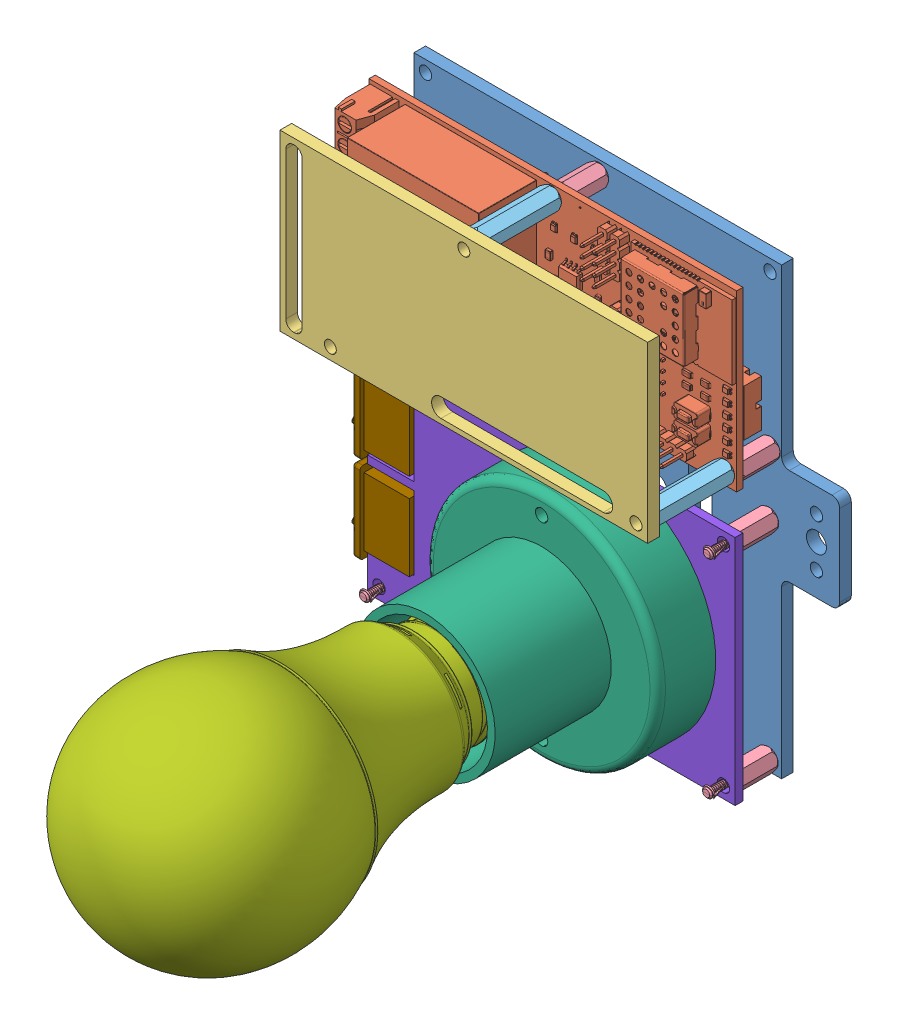
SolidWorks assembly Assem, configuration Default. Lengths in mm.
Overall size (137.27 153.42 149.57).
18 component instances, 9 part files, 43 mates.
Components (placement in the parent):
- frame_rtls-1: frame_rtls [Default] at (-50.2519 61.609 0) size (125.02 115.01 3)
- RTLS-1: RTLS [Default] at (0 118.9041 14.6194) x (-1 0 0) z (0 0 1) size (100.23 52.22 33.77)
- frame_rtls_top-1: frame_rtls_top [Default] at (-39.2593 131.0198 34.6194) x (-1 0 0) z (0 0 1) size (95 45.01 3)
- Hex Spacer MF M3 L10mm.stp-1: Hex Spacer MF M3 L10mm.stp [Default] at (-120.6382 86.5408 13) x (0.972076 -0.234665 0) z (0 0 1) size (35.27 35.27 35.27)
- Hex Spacer MF M3 L10mm.stp-2: Hex Spacer MF M3 L10mm.stp [Default] at (-87.1957 116.7477 13) x (0.999688 -0.024974 0) z (0 0 1) size (35.27 35.27 35.27)
- Hex Spacer MF M3 L10mm.stp-3: Hex Spacer MF M3 L10mm.stp [Default] at (-39.7266 61.0145 13) x (0.921221 0.38904 0) z (0 0 1) size (35.27 35.27 35.27)
- Hex Spacer MF M3 L20mm.stp-1: Hex Spacer MF M3 L20mm.stp [Default] at (136.3996 89.8518 14.6194) x (-0.995937 -0.090058 0) z (0 0 -1) size (35.27 35.27 37.7)
- Hex Spacer MF M3 L20mm.stp-2: Hex Spacer MF M3 L20mm.stp [Default] at (-122.1152 -2.5556 14.6194) x (0.530847 0.847468 0) z (0 0 -1) size (35.27 35.27 37.7)
- Hex Spacer MF M3 L20mm.stp-3: Hex Spacer MF M3 L20mm.stp [Default] at (-150.1721 -44.9927 14.6194) x (0.488573 0.872523 0) z (0 0 -1) size (35.27 35.27 37.7)
- lightBulbHolder-1: lightBulbHolder [Default] at (-35.021 33.8951 30) x (0 -1 0) z (0 0 -1) size (60 60 45)
- E27 400L-1: E27 400L [Default] at (-62.6296 46.4675 35) x (0.913942 -0.405844 0) z (-0.405844 -0.913942 0) size (61.78 110 61.78)
- frame_rtls_mid-1: frame_rtls_mid [Default] at (-55.4574 45.0136 13) size (95 60 2)
- Hex Spacer MF M3 L10mm.stp-4: Hex Spacer MF M3 L10mm.stp [Default] at (-5.8964 20.6716 13) x (0.066123 0.997811 0) z (0 0 1) size (35.27 35.27 35.27)
- Hex Spacer MF M3 L10mm.stp-5: Hex Spacer MF M3 L10mm.stp [Default] at (-116.6357 28.8809 13) x (0.607256 0.794506 0) z (0 0 1) size (35.27 35.27 35.27)
- Hex Spacer MF M3 L10mm.stp-6: Hex Spacer MF M3 L10mm.stp [Default] at (-96.1069 -33.2978 13) x (0.101079 0.994878 0) z (0 0 1) size (35.27 35.27 35.27)
- Hex Spacer MF M3 L10mm.stp-7: Hex Spacer MF M3 L10mm.stp [Default] at (-5.1443 -33.0494 13) x (0.043617 0.999048 0) z (0 0 1) size (35.27 35.27 35.27)
- rocker_switch-1: rocker_switch [test] at (-97.021 45.1451 9.45) x (0 0 1) z (-1 0 0) size (15 21 21.16)
- rocker_switch-2: rocker_switch [test] at (-97.021 22.6451 9.45) x (0 0 1) z (-1 0 0) size (15 21 21.16)
Mates (geometry in assembly coordinates):
- Coincident59: coincident aligned: plane of RTLS-1 through (0 118.9041 13) normal (1 0 0); plane of frame_rtls-1 through (0 46.8951 3) normal (1 0 0)
- Coincident60: coincident anti-aligned: plane of frame_rtls-1 through (2 75.9041 0) normal (0 0 -1)
- Coincident61: coincident anti-aligned: plane of frame_rtls-1 through (2 75.9041 3) normal (0 0 1); plane of Hex Spacer MF M3 L10mm.stp-1 through (-84.8324 75.2738 3) normal (0 0 -1)
- Tangent1: tangent anti-aligned: cylinder of frame_rtls-1 through (-82 76.9041 3) axis (0 0 -1) radius 1.55; face of Hex Spacer MF M3 L10mm.stp-1
- Coincident63: coincident anti-aligned: plane of frame_rtls-1 through (2 75.9041 3) normal (0 0 1); plane of Hex Spacer MF M3 L10mm.stp-3 through (-4.2348 73.235 3) normal (0 0 -1)
- Coincident64: coincident aligned: plane of frame_rtls-1 through (0 46.8951 3) normal (1 0 0)
- Tangent2: tangent anti-aligned: cylinder of frame_rtls-1 through (-3 76.9041 3) axis (0 0 -1) radius 1.55; edge_curve of Hex Spacer MF M3 L10mm.stp-3
- Coincident65: coincident anti-aligned: plane of frame_rtls-1 through (2 75.9041 3) normal (0 0 1); plane of Hex Spacer MF M3 L10mm.stp-2 through (-49.821 113.2632 3) normal (0 0 -1)
- Tangent3: tangent anti-aligned: cylinder of frame_rtls-1 through (-47.5105 115.925 3) axis (0 0 -1) radius 1.55; edge_curve of Hex Spacer MF M3 L10mm.stp-2
- Coincident66: coincident anti-aligned: plane of RTLS-1 through (0 118.9041 13) normal (0 0 -1); plane of Hex Spacer MF M3 L10mm.stp-3 through (-4.2348 73.235 13) normal (0 0 1)
- Coincident67: coincident anti-aligned: plane of frame_rtls-1 through (2 75.9041 3) normal (0 0 1); plane of Hex Spacer MF M3 L10mm.stp-5 through (-91.868 57.0867 3) normal (0 0 -1)
- Coincident68: coincident anti-aligned: plane of frame_rtls-1 through (2 75.9041 3) normal (0 0 1); plane of Hex Spacer MF M3 L10mm.stp-4 through (-0.8757 57.871 3) normal (0 0 -1)
- Coincident69: coincident anti-aligned: plane of frame_rtls-1 through (2 75.9041 3) normal (0 0 1); plane of Hex Spacer MF M3 L10mm.stp-6 through (-89.7846 3.7027 3) normal (0 0 -1)
- Coincident70: coincident anti-aligned: plane of frame_rtls-1 through (2 75.9041 3) normal (0 0 1); plane of Hex Spacer MF M3 L10mm.stp-7 through (-0.9633 4.2537 3) normal (0 0 -1)
- Tangent4: tangent anti-aligned: cylinder of frame_rtls-1 through (-3 6.8951 3) axis (0 0 -1) radius 1.6; edge_curve of Hex Spacer MF M3 L10mm.stp-7
- Tangent5: tangent anti-aligned: cylinder of frame_rtls-1 through (-3 60.8951 3) axis (0 0 -1) radius 1.6; edge_curve of Hex Spacer MF M3 L10mm.stp-4
- Tangent6: tangent anti-aligned: cylinder of frame_rtls-1 through (-92.021 6.8951 3) axis (0 0 -1) radius 1.6; edge_curve of Hex Spacer MF M3 L10mm.stp-6
- Tangent7: tangent anti-aligned: cylinder of frame_rtls-1 through (-92.021 60.8951 3) axis (0 0 -1) radius 1.6; edge_curve of Hex Spacer MF M3 L10mm.stp-5
- Coincident71: coincident anti-aligned: plane of lightBulbHolder-1 through (-35.021 33.8951 35) normal (0 0 1); plane of E27 400L-1 through (-35.2113 34.2922 35) normal (0 0 -1)
- Tangent8: tangent aligned: cylinder of lightBulbHolder-1 through (-35.021 33.8951 60) axis (0 0 -1) radius 18; edge_curve of E27 400L-1
- Coincident80: coincident anti-aligned: plane of RTLS-1 through (0 118.9041 14.6194) normal (0 0 1); plane of Hex Spacer MF M3 L20mm.stp-3 through (-85.2428 76.1815 14.6194) normal (0 0 -1)
- Coincident81: coincident anti-aligned: plane of RTLS-1 through (0 118.9041 14.6194) normal (0 0 1); plane of Hex Spacer MF M3 L20mm.stp-1 through (-0.2622 74.9336 14.6194) normal (0 0 -1)
- Coincident82: coincident anti-aligned: plane of RTLS-1 through (0 118.9041 14.6194) normal (0 0 1); plane of Hex Spacer MF M3 L20mm.stp-2 through (-51.3113 115.2825 14.6194) normal (0 0 -1)
- Coincident86: coincident aligned: plane of frame_rtls-1 through (0 46.8951 3) normal (1 0 0); plane of frame_rtls_top-1 through (0 73.8951 37.6194) normal (1 0 0)
- Coincident87: coincident anti-aligned: plane of frame_rtls_top-1 through (-39.2593 131.0198 34.6194) normal (0 0 -1); plane of Hex Spacer MF M3 L20mm.stp-1 through (-0.2622 74.9336 34.6194) normal (0 0 1)
- Tangent14: tangent anti-aligned: cylinder of frame_rtls_top-1 through (-3 76.8951 37.6194) axis (0 0 -1) radius 1.55; edge_curve of Hex Spacer MF M3 L20mm.stp-1
- Tangent15: tangent anti-aligned: cylinder of frame_rtls_top-1 through (-82 76.8951 37.6194) axis (0 0 -1) radius 1.55; edge_curve of Hex Spacer MF M3 L20mm.stp-3
- Tangent16: tangent anti-aligned: cylinder of frame_rtls_top-1 through (-47.5 115.9041 37.6194) axis (0 0 -1) radius 1.55; edge_curve of Hex Spacer MF M3 L20mm.stp-2
- Coincident88: coincident anti-aligned: plane of frame_rtls-1 through (2 75.9041 3) normal (0 0 1); plane of rocker_switch-1 through (-83.321 36.3951 3) normal (0 0 -1)
- Coincident89: coincident anti-aligned: plane of frame_rtls-1 through (2 75.9041 3) normal (0 0 1); plane of rocker_switch-2 through (-83.321 13.8951 3) normal (0 0 -1)
- Coincident94: coincident anti-aligned: plane of frame_rtls-1 through (2 75.9041 3) normal (0 0 1); plane of rocker_switch-1 through (-83.321 36.3951 3) normal (0 0 -1)
- Coincident95: coincident anti-aligned: plane of frame_rtls_mid-1 through (-95.021 53.8951 15) normal (0 -1 0); plane of rocker_switch-1 through (-83.321 53.8951 15.9) normal (0 1 0)
- Coincident96: coincident anti-aligned: plane of frame_rtls_mid-1 through (-95.021 63.8951 15) normal (-1 0 0); plane of rocker_switch-1 through (-95.021 55.6451 1.95) normal (1 0 0)
- Coincident98: coincident anti-aligned: plane of frame_rtls_mid-1 through (-55.4574 45.0136 13) normal (0 0 -1); plane of Hex Spacer MF M3 L10mm.stp-5 through (-91.868 57.0867 13) normal (0 0 1)
- Coincident99: coincident aligned: plane of frame_rtls-1 through (-95.021 3.8951 3) normal (0 -1 0); plane of frame_rtls_mid-1 through (-95.021 3.8951 15) normal (0 -1 0)
- Coincident102: coincident anti-aligned: plane of frame_rtls_mid-1 through (-95.021 13.8951 15) normal (-1 0 0); plane of rocker_switch-2 through (-95.021 33.1451 1.95) normal (1 0 0)
- Coincident103: coincident anti-aligned: plane of lightBulbHolder-1 through (-35.021 33.8951 15) normal (0 0 -1); plane of frame_rtls_mid-1 through (-55.4574 45.0136 15) normal (0 0 1)
- Concentric4: concentric anti-aligned: cylinder of lightBulbHolder-1 through (-35.021 58.8951 15) axis (0 0 1) radius 1.6; cylinder of frame_rtls_mid-1 through (-35.021 58.8951 15) axis (0 0 -1) radius 1.6
- Concentric5: concentric anti-aligned: cylinder of lightBulbHolder-1 through (-35.021 8.8951 15) axis (0 0 1) radius 1.6; cylinder of frame_rtls_mid-1 through (-35.021 8.8951 15) axis (0 0 -1) radius 1.6
- Coincident104: coincident anti-aligned: plane of frame_rtls_mid-1 through (-95.021 13.8951 15) normal (0 1 0); plane of rocker_switch-2 through (-83.321 13.8951 3) normal (0 -1 0)
- Coincident105: coincident aligned: plane of frame_rtls-1 through (0 118.9041 3) normal (0 1 0); plane of frame_rtls_top-1 through (0 118.9041 37.6194) normal (0 1 0)
- Coincident106: coincident aligned: plane of frame_rtls-1 through (0 118.9041 3) normal (0 1 0); plane of RTLS-1 through (-95.021 118.9041 13) normal (0 1 0)
- Coincident107: coincident aligned: plane of frame_rtls-1 through (-95.021 46.8951 3) normal (-1 0 0); plane of frame_rtls_mid-1 through (-95.021 63.8951 15) normal (-1 0 0)
